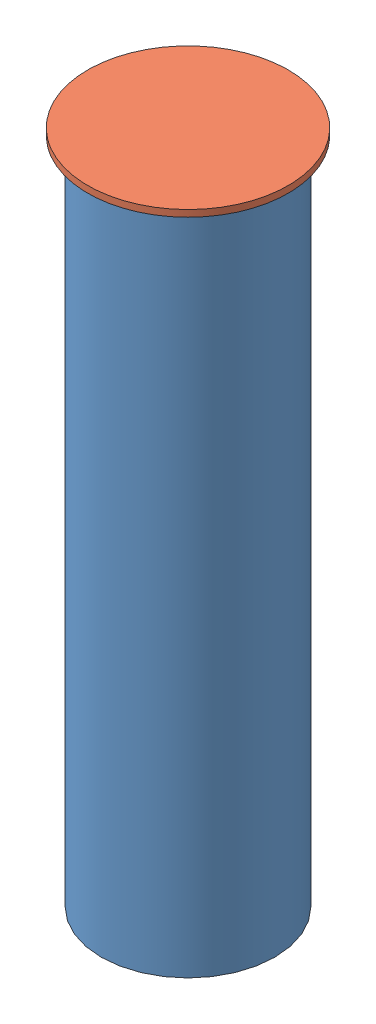
SolidWorks assembly Hülle, configuration Standard. Lengths in mm.
Overall size (83.05 202 83.05).
2 component instances, 2 part files, 2 mates.
Components (placement in the parent):
- Rohr-1: Rohr [Standard] at (-6.2133 -99.6117 200) size (52 200 52)
- Deckel-1: Deckel [Standard] at (-6.2133 102.3883 200) x (-0.837169 0 -0.546944) z (-0.546944 0 0.837169) size (60 12 60)
Mates (geometry in assembly coordinates):
- Deckungsgleich1: coincident: plane of Rohr-1 through (-6.2133 100.3883 200) normal (0 1 0); plane of Deckel-1 through (-6.2133 100.3883 200) normal (0 -1 0)
- Konzentrisch1: concentric anti-aligned: cylinder of Rohr-1 through (-6.2133 100.3883 200) axis (0 -1 0) radius 25; cylinder of Deckel-1 through (-6.2133 90.3883 200) axis (0 1 0) radius 25
